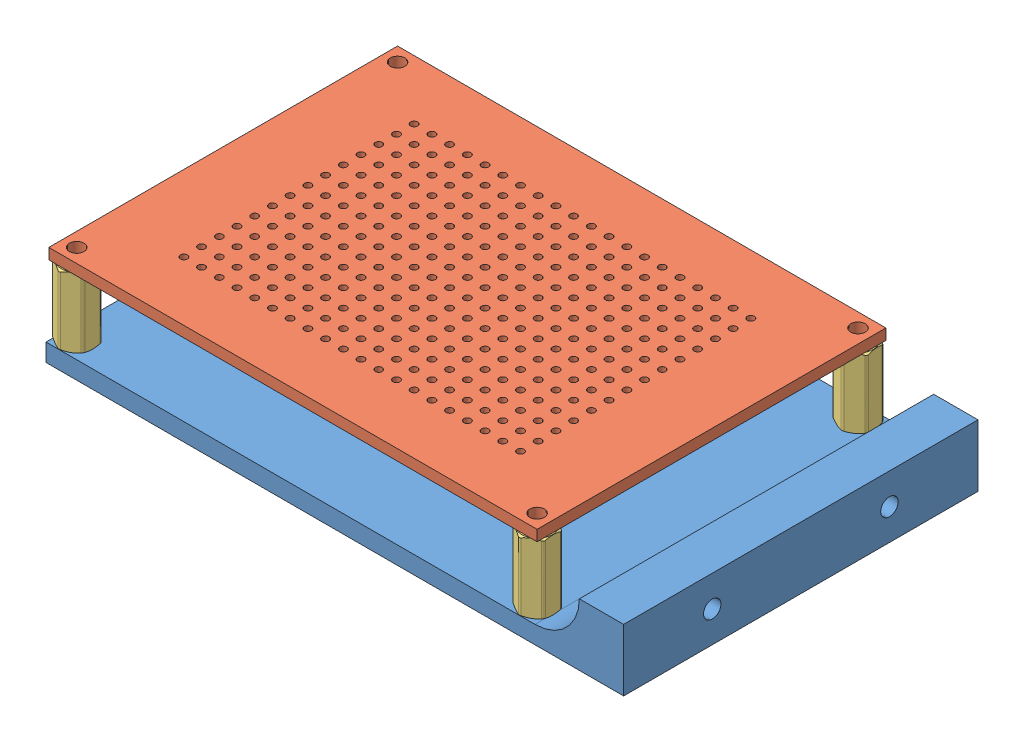
SolidWorks assembly perfboard_assemblly, configuration Default. Lengths in mm.
Overall size (85.34 24.41 63.5).
11 component instances, 3 part files, 14 mates.
Components (placement in the parent):
- perfboard_mount-1: perfboard_mount [Default] at origin size (85.34 22.86 63.5)
- perfboard_20x14-1: perfboard_20x14 [Default] at (-41.402 11.27 25) size (70 1.55 50)
- M2 Standoff-1: M2 Standoff [93655A096] at (-39.402 1.27 -23) x (1 0 0) z (0 1 0) size (4.5 5.08 14.09)
- M2 Standoff-2: M2 Standoff [93655A096] at (26.598 1.27 -23) x (0.994909 0 -0.100776) z (0 1 0) size (4.5 5.08 14.09)
- M2 Standoff-3: M2 Standoff [93655A096] at (26.598 1.27 23) x (1 0 0) z (0 1 0) size (4.5 5.08 14.09)
- M2 Standoff-4: M2 Standoff [93655A096] at (-39.402 1.27 23) x (1 0 0) z (0 1 0) size (4.5 5.08 14.09)
- perfboard_20x14-2: perfboard_20x14 [Default] at (-41.402 22.7 25) size (70 1.55 50) (suppressed, hidden)
- M2 Standoff-5: M2 Standoff [93655A096] at (26.598 12.7 23) x (1 0 0) z (0 1 0) size (4.5 5.08 14.09) (suppressed, hidden)
- M2 Standoff-6: M2 Standoff [93655A096] at (-39.402 12.7 23) x (1 0 0) z (0 1 0) size (4.5 5.08 14.09) (suppressed, hidden)
- M2 Standoff-7: M2 Standoff [93655A096] at (-39.402 12.7 -23) x (1 0 0) z (0 1 0) size (4.5 5.08 14.09) (suppressed, hidden)
- M2 Standoff-8: M2 Standoff [93655A096] at (26.598 12.7 -23) x (0.994909 0 -0.100776) z (0 1 0) size (4.5 5.08 14.09) (suppressed, hidden)
Mates (geometry in assembly coordinates):
- Coincident1: coincident aligned: plane of perfboard_mount-1 through (0 0 0) normal (0 0 1)
- Coincident2: coincident aligned: plane of perfboard_mount-1 through (0 0 0) normal (0 1 0)
- Coincident3: coincident aligned: plane of perfboard_mount-1 through (0 0 0) normal (1 0 0)
- Coincident4: coincident: plane of perfboard_mount-1 through (-41.402 1.27 25.4) normal (-1 0 0); plane of perfboard_20x14-1 through (-41.402 12.82 25) normal (-1 0 0)
- Coincident5: coincident aligned: plane of perfboard_20x14-1 through (-41.402 11.27 0) normal (0 0 1)
- Concentric11: concentric aligned: cylinder of perfboard_20x14-1 through (-39.402 12.82 -23) axis (0 -1 0) radius 1.05; cone of M2 Standoff-1 through (-39.402 11.27 -23) axis (0 -1 0)
- Coincident61: coincident anti-aligned: plane of perfboard_20x14-1 through (-41.402 11.27 25) normal (0 -1 0); plane of M2 Standoff-1 through (-39.402 11.27 -24.225) normal (0 1 0)
- Concentric21: concentric aligned: cylinder of perfboard_20x14-1 through (26.598 12.82 -23) axis (0 -1 0) radius 1.05; cone of M2 Standoff-2 through (26.598 11.27 -23) axis (0 -1 0)
- Coincident71: coincident anti-aligned: plane of perfboard_20x14-1 through (-41.402 11.27 25) normal (0 -1 0); plane of M2 Standoff-2 through (26.4745 11.27 -24.2188) normal (0 1 0)
- Concentric31: concentric aligned: cylinder of perfboard_20x14-1 through (26.598 12.82 23) axis (0 -1 0) radius 1.05; cone of M2 Standoff-3 through (26.598 11.27 23) axis (0 -1 0)
- Coincident81: coincident anti-aligned: plane of perfboard_20x14-1 through (-41.402 11.27 25) normal (0 -1 0); plane of M2 Standoff-3 through (26.598 11.27 21.775) normal (0 1 0)
- Concentric41: concentric aligned: cylinder of perfboard_20x14-1 through (-39.402 12.82 23) axis (0 -1 0) radius 1.05; cone of M2 Standoff-4 through (-39.402 11.27 23) axis (0 -1 0)
- Coincident91: coincident anti-aligned: plane of perfboard_20x14-1 through (-41.402 11.27 25) normal (0 -1 0); plane of M2 Standoff-4 through (-39.402 11.27 21.775) normal (0 1 0)
- Coincident10: coincident anti-aligned: plane of perfboard_mount-1 through (0 1.27 0) normal (0 1 0); plane of M2 Standoff-1 through (-39.402 1.27 -23.9327) normal (0 -1 0)
